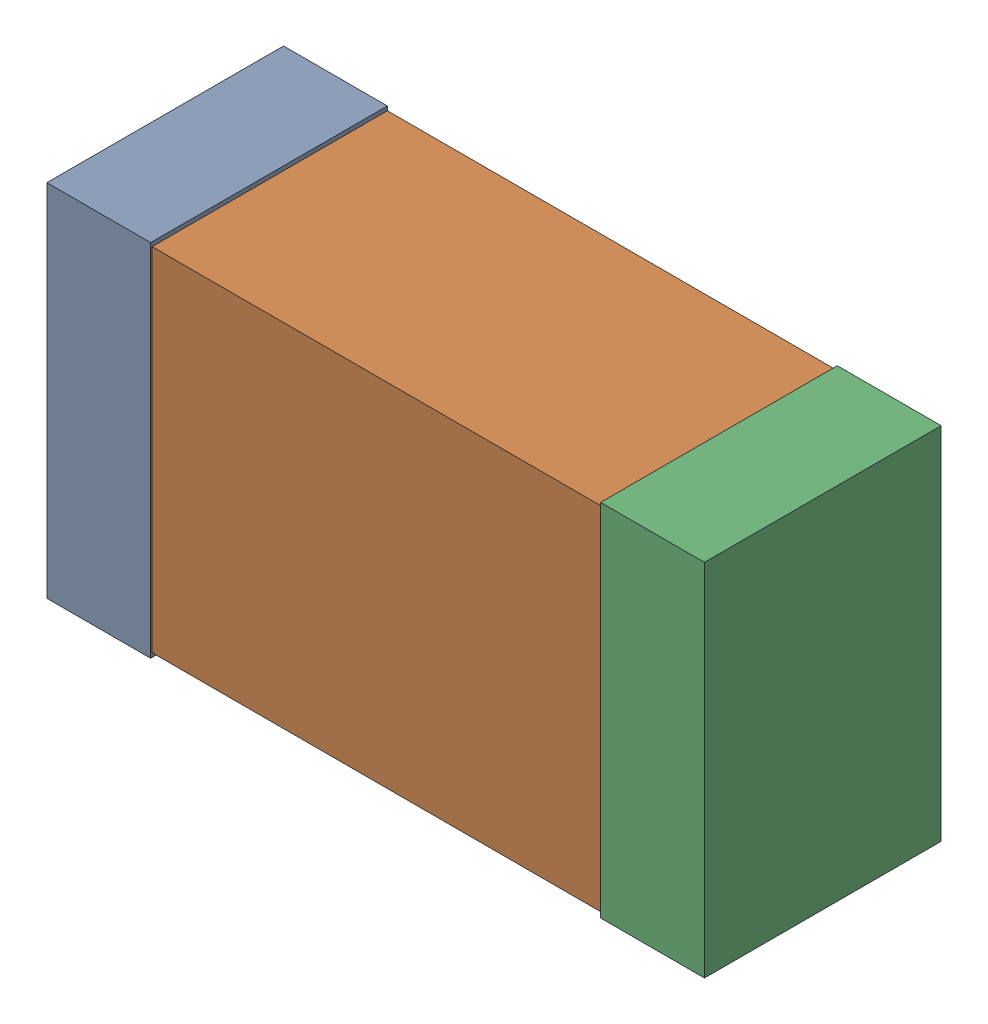
SolidWorks assembly C4Kanaloa_v2.0.0_GPIO_b_1, configuration Default. Lengths in mm.
Overall size (2.38 1.3 0.85).
6 component instances, 2 part files, 0 mates.
Components (placement in the parent):
- 352877648-1: 352877648 [Default] at (61.738 50.546 0) size (0.38 1.3 0.85)
  - Extruded_14-1: Extruded_14 [Default] at origin size (0.38 1.3 0.85)
- 352877904-1: 352877904 [Default] at (62.738 50.546 0) size (2.2 1.27 0.85)
  - Extruded_18-1: Extruded_18 [Default] at origin size (2.2 1.27 0.85)
- 352877648-2: 352877648 [Default] at (63.738 50.546 0) size (0.38 1.3 0.85)
  - Extruded_14-1: Extruded_14 [Default] at origin size (0.38 1.3 0.85)
